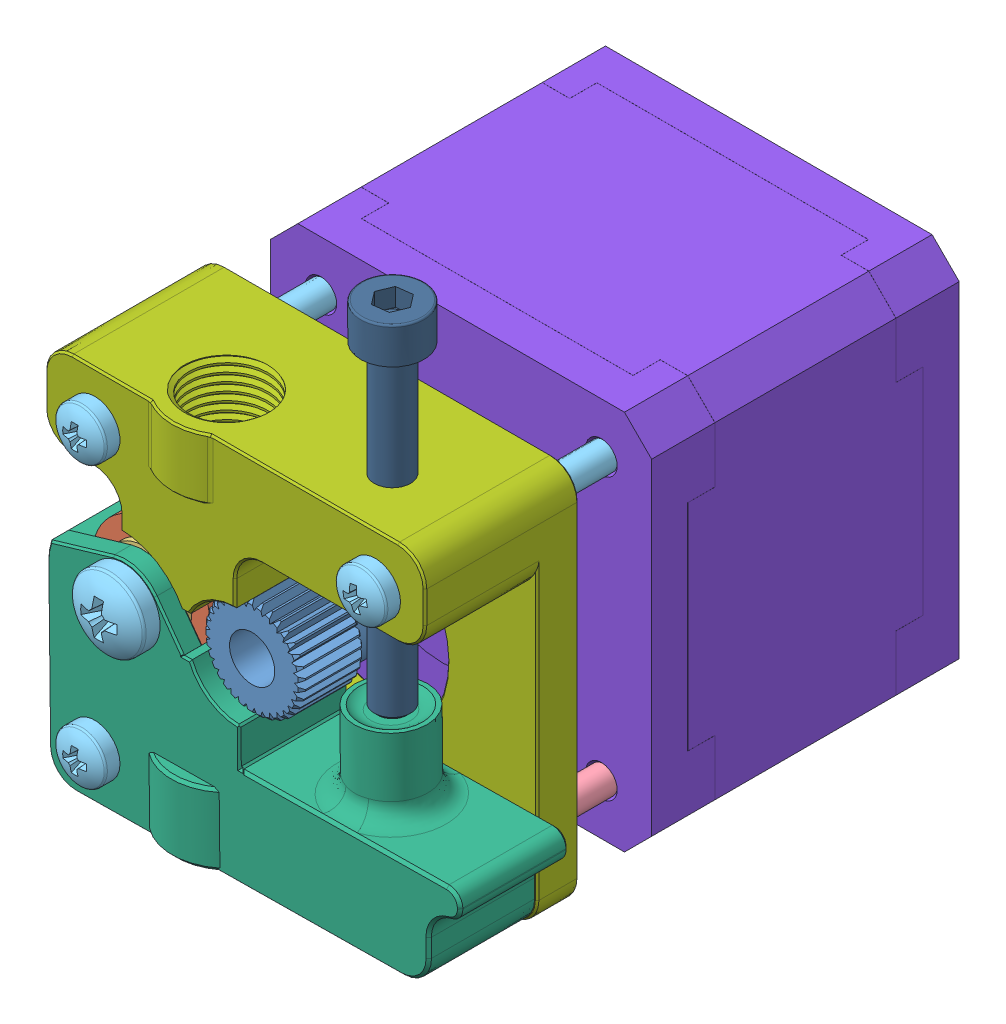
SolidWorks assembly Modified extruder cold end mirror, configuration По умолчанию. Lengths in mm.
Overall size (46.68 59.01 61.62).
15 component instances, 10 part files, 23 mates.
Components (placement in the parent):
- Extruder Gear-1: Extruder Gear [По умолчанию] at (19.1416 -89.9754 11.3234) x (0 1 0) z (0 0 -1) size (10.99 10.98 11)
- bearing assembly for cold end-1: bearing assembly for cold end [Default] at (0.8707 -88.773 18.2154) x (-0.244327 0.969693 0) z (0 0 1) size (15.92 15.92 5.5)
  - Bearing for Filament (U694)-1: Bearing for Filament (U694) [По умолчанию] at (-2.9876 -5.0242 -8.392) x (0 0 -1) z (0.258674 0.965965 0) size (4 13 13)
  - washer m4 .75mm-1: washer m4 .75mm [Default] at (2.4574 -4.5123 -8.392) x (0.589313 -0.807905 0) z (0 0 1) size (9 9 0.75)
  - washer m4 .75mm-2: washer m4 .75mm [Default] at (-3.9864 0.3528 -13.142) x (0.751721 0.659482 0) z (0 0 1) size (9 9 0.75)
- countersunk flat head cross recess screw_iso1-2: countersunk flat head cross recess screw_iso1 [ISO 7046-1 - M3 x 16 - Z --- 16N] at (34.6416 -105.4754 0.8234) x (0 0 -1) z (-0.420495 -0.907295 0) size (16 5.5 5.5)
- pan head cross recess screw_iso1-14: pan head cross recess screw_iso1 [ISO 7045 - M4 x 12 - Z --- 12N] at (6.4726 -90.4425 15.9234) x (0 0 -1) z (1 0 0) size (15.02 8 8)
- Extruder Lever (mirrored) 4-1: Extruder Lever (mirrored) 4 [По умолчанию] at (-2.1 -84.0386 0.8234) x (-0.999937 -0.011255 0) z (0 0 1) size (45.54 27.33 13.33)
- Extruder Bracket (mirrored)hacked for no bolden-3: Extruder Bracket (mirrored)hacked for no bolden [По умолчанию] at (-1.8584 -68.9754 -3.7766) x (-1 0 0) z (0 0 1) size (42 42.33 17.93)
- Extruder Steper Motor (needs reference)2-1: Extruder Steper Motor (needs reference)2 [Default] at (19.1416 -89.9754 -45.7766) x (0 1 0) z (0 0 1) size (42.1 42.1 53.1)
- pan head cross recess screw_iso1-15: pan head cross recess screw_iso1 [ISO 7045 - M3 x 30 - Z --- 25N] at (34.6416 -74.4754 15.6234) x (0 0 -1) z (-0.168641 0.985677 0) size (32.35 5.6 5.6)
- pan head cross recess screw_iso1-16: pan head cross recess screw_iso1 [ISO 7045 - M3 x 30 - Z --- 25N] at (3.6416 -74.4754 15.6234) x (0 0 -1) z (0 1 0) size (32.35 5.6 5.6)
- pan head cross recess screw_iso1-17: pan head cross recess screw_iso1 [ISO 7045 - M3 x 30 - Z --- 25N] at (3.6416 -105.4754 15.6234) x (0 0 -1) z (1 0 0) size (32.35 5.6 5.6)
- socket set screw cone point_iso1-1: socket set screw cone point_iso1 [ISO 4027 - M2 x 3-N] at (14.6416 -89.9754 2.3234) x (1 0 0) z (0 0.924225 0.381849) size (3 2 2)
- socket head cap screw_iso1-3: socket head cap screw_iso1 [ISO 4762 M4 x 35 --- 20N] at (30.1416 -52.3593 6.8234) x (0 -1 0) z (-0.794697 0 0.607007) size (39 7 7)
Mates (geometry in assembly coordinates):
- Concentric3: concentric anti-aligned: cylinder of Extruder Lever (mirrored) 4-1 through (3.6416 -105.4754 -10.6766) axis (0 0 1) radius 1.7; cylinder of Extruder Bracket (mirrored)hacked for no bolden-3 through (3.6416 -105.4754 22.2234) axis (0 0 -1) radius 1.75
- Coincident3: coincident anti-aligned: plane of Extruder Lever (mirrored) 4-1 through (-2.1 -84.0386 0.8234) normal (0 0 -1); plane of Extruder Bracket (mirrored)hacked for no bolden-3 through (6.4787 -90.6754 0.8234) normal (0 0 1)
- Concentric7: concentric anti-aligned: cylinder of bearing assembly for cold end-1/Bearing for Filament (U694)-1 through (6.4726 -90.4425 2.6353) axis (0 0 -1) radius 2; cylinder of pan head cross recess screw_iso-14 through (6.4726 -90.4425 41.3234) axis (0 0 1) radius 2
- Concentric8: concentric aligned: cylinder of pan head cross recess screw_iso-14 through (6.4726 -90.4425 41.3234) axis (0 0 1) radius 2; cylinder of Extruder Lever (mirrored) 4-1 through (6.4726 -90.4425 12.8234) axis (0 0 1) radius 2.15
- Coincident9: coincident anti-aligned: plane of bearing assembly for cold end-1/washer m4 .75mm-2 through (6.4726 -90.4425 5.0734) normal (0 0 -1); plane of Extruder Lever (mirrored) 4-1 through (6.4726 -90.4425 5.0734) normal (0 0 1)
- Concentric9: concentric anti-aligned: cylinder of countersunk flat head cross recess screw_iso-2 through (34.6416 -105.4754 7.1734) axis (0 0 1) radius 1.5; cylinder of Extruder Bracket (mirrored)hacked for no bolden-3 through (34.6416 -105.4754 22.2234) axis (0 0 -1) radius 1.75
- Coincident10: coincident aligned: cone of countersunk flat head cross recess screw_iso-2 through (34.6416 -105.4754 0.4234) axis (0 0 -1); cone of Extruder Bracket (mirrored)hacked for no bolden-3 through (34.6416 -105.4754 0.8234) axis (0 0 -1)
- Distance2: distance = 8 mm anti-aligned: plane of Extruder Bracket (mirrored)hacked for no bolden-3 through (-1.8584 -68.9754 -3.7766) normal (0 0 -1); plane of Extruder Steper Motor (needs reference)2-1 through (-1.9084 -68.9254 -11.7766) normal (0 0 1)
- Concentric401183: concentric aligned: cylinder of Extruder Bracket (mirrored)hacked for no bolden-3 through (34.6416 -105.4754 22.2234) axis (0 0 -1) radius 1.75; circle of Extruder Steper Motor (needs reference)2-1
- Concentric401187: concentric anti-aligned: cylinder of Extruder Bracket (mirrored)hacked for no bolden-3 through (3.6416 -74.4754 22.2234) axis (0 0 -1) radius 1.75; cylinder of Extruder Steper Motor (needs reference)2-1 through (3.6416 -74.4754 -11.7766) axis (0 0 1) radius 1.25
- Concentric401186: concentric anti-aligned: cylinder of pan head cross recess screw_iso-15 through (34.6416 -74.4754 41.0234) axis (0 0 1) radius 1.5; cylinder of Extruder Bracket (mirrored)hacked for no bolden-3 through (34.6416 -74.4754 22.2234) axis (0 0 -1) radius 1.75
- Concentric6: concentric aligned: cylinder of pan head cross recess screw_iso-17 through (3.6416 -105.4754 41.0234) axis (0 0 1) radius 1.5; cylinder of Extruder Lever (mirrored) 4-1 through (3.6416 -105.4754 -10.6766) axis (0 0 1) radius 1.7
- Coincident787249: coincident anti-aligned: plane of pan head cross recess screw_iso-14 through (6.4726 -88.4425 12.8234) normal (0 0 -1); plane of Extruder Lever (mirrored) 4-1 through (-2.1 -84.0386 12.8234) normal (0 0 1)
- Concentric401188: concentric anti-aligned: cylinder of Extruder Bracket (mirrored)hacked for no bolden-3 through (3.6416 -74.4754 22.2234) axis (0 0 -1) radius 1.75; cylinder of pan head cross recess screw_iso-16 through (3.6416 -74.4754 41.0234) axis (0 0 1) radius 1.5
- Coincident787258: coincident anti-aligned: plane of Extruder Bracket (mirrored)hacked for no bolden-3 through (-1.8584 -68.9754 13.2234) normal (0 0 1); plane of pan head cross recess screw_iso-15 through (33.1631 -74.7283 13.2234) normal (0 0 -1)
- Coincident787251: coincident aligned: plane of pan head cross recess screw_iso-15 through (33.1631 -74.7283 13.2234) normal (0 0 -1); plane of pan head cross recess screw_iso-16 through (2.1416 -74.4754 13.2234) normal (0 0 -1)
- Coincident787252: coincident aligned: plane of pan head cross recess screw_iso-16 through (2.1416 -74.4754 13.2234) normal (0 0 -1); plane of pan head cross recess screw_iso-17 through (3.6416 -103.9754 13.2234) normal (0 0 -1)
- Concentric401189: concentric anti-aligned: cylinder of Extruder Gear-1 through (19.1416 -89.9754 0.3234) axis (0 0 1) radius 2.5; cylinder of Extruder Steper Motor (needs reference)2-1 through (19.1416 -89.9754 7.3234) axis (0 0 -1) radius 2.5
- Concentric4011901: concentric anti-aligned: cylinder of Extruder Gear-1 through (11.6416 -89.9754 2.3234) axis (1 0 0) radius 1.1; cylinder of socket set screw cone point_iso-1 through (1.9416 -89.9754 2.3234) axis (-1 0 0) radius 1
- Coincident787253: coincident: plane of Extruder Steper Motor (needs reference)2-1 through (17.6416 -91.9754 -6.6766) normal (-1 0 0); point of socket set screw cone point_iso-1
- Distance3: distance = 4 mm aligned: plane of Extruder Gear-1 through (19.1416 -89.9754 11.3234) normal (0 0 1); plane of Extruder Steper Motor (needs reference)2-1 through (19.1416 -89.9754 7.3234) normal (0 0 1)
- Parallel1: parallel aligned: plane of Extruder Steper Motor (needs reference)2-1 through (17.6416 -91.9754 -6.6766) normal (-1 0 0); plane of socket set screw cone point_iso-1 through (14.6416 -89.9754 2.3234) normal (-1 0 0)
- Concentric4011904: concentric aligned: cylinder of socket head cap screw_iso-3 through (30.1416 -20.6093 6.8234) axis (0 1 0) radius 3.5; cylinder of Extruder Bracket (mirrored)hacked for no bolden-3 through (30.1416 -68.9754 6.8234) axis (0 1 0) radius 1.65
